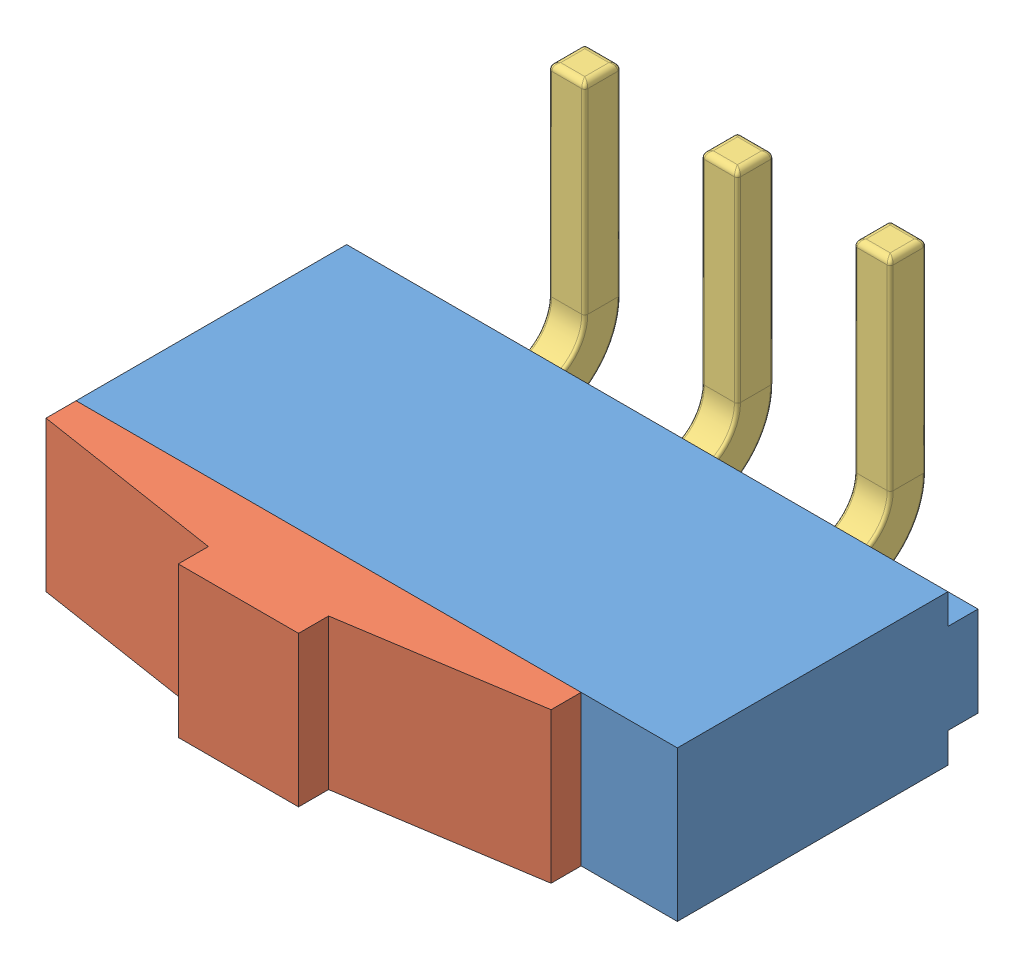
SolidWorks assembly vypinac, configuration Výchozí. Lengths in mm.
Overall size (10 5.6 7.8).
5 component instances, 3 part files, 12 mates.
Components (placement in the parent):
- zaklad-1: zaklad [Výchozí] at origin size (10 2.5 5)
- cudlik-1: cudlik [Výchozí] at (-0.8 -1.25 5.75) x (-1 0 0) z (0 0 -1) size (8.4 2.5 1.5)
- vyvod-3: vyvod [Výchozí] at (-2.54 4.255 -1) x (0 1 0) z (1 0 0) size (4.65 2.3 0.6)
- vyvod-4: vyvod [Výchozí] at (0 4.255 -1) x (0 1 0) z (1 0 0) size (4.65 2.3 0.6)
- vyvod-5: vyvod [Výchozí] at (2.54 4.255 -1) x (0 1 0) z (1 0 0) size (4.65 2.3 0.6)
Mates (geometry in assembly coordinates):
- Sjednocená1: coincident anti-aligned: plane of zaklad-1 through (0 0 5) normal (0 0 1); plane of cudlik-1 through (-5 1.25 5) normal (0 0 -1)
- Sjednocená2: coincident aligned: plane of zaklad-1 through (5 1.25 5) normal (0 1 0); plane of cudlik-1 through (-0.8 1.25 5.75) normal (0 1 0)
- Sjednocená3: coincident aligned: plane of zaklad-1 through (-5 1.25 5) normal (-1 0 0); plane of cudlik-1 through (-5 1.25 5) normal (-1 0 0)
- Sjednocená4: coincident: plane of zaklad-1 through (2.54 0 1) normal (0 0 -1); plane of vyvod-5 through (2.79 -0.25 1) normal (0 0 1)
- Soustředná1: concentric: cylinder of zaklad-1 through (2.54 0 1) axis (0 0 -1) radius 0.25; cylinder of vyvod-5 through (2.54 0 0) axis (0 0 1) radius 0.25
- Rovnoběžná1: parallel aligned: plane of zaklad-1 through (5 1.25 5) normal (0 1 0); plane of vyvod-5 through (2.79 4.35 -1.25) normal (0 1 0)
- Sjednocená6: coincident: plane of zaklad-1 through (0 0 1) normal (0 0 -1); plane of vyvod-4 through (0.25 -0.25 1) normal (0 0 1)
- Sjednocená7: coincident: plane of zaklad-1 through (-2.54 0 1) normal (0 0 -1); plane of vyvod-3 through (-2.29 -0.25 1) normal (0 0 1)
- Soustředná2: concentric: cylinder of zaklad-1 through (0 0 1) axis (0 0 -1) radius 0.25; cylinder of vyvod-4 through (0 0 0) axis (0 0 1) radius 0.25
- Soustředná3: concentric: cylinder of zaklad-1 through (-2.54 0 1) axis (0 0 -1) radius 0.25; cylinder of vyvod-3 through (-2.54 0 0) axis (0 0 1) radius 0.25
- Rovnoběžná2: parallel aligned: plane of zaklad-1 through (5 1.25 5) normal (0 1 0); plane of vyvod-4 through (0.25 4.35 -1.25) normal (0 1 0)
- Rovnoběžná3: parallel aligned: plane of zaklad-1 through (5 1.25 5) normal (0 1 0); plane of vyvod-3 through (-2.29 4.35 -1.25) normal (0 1 0)
